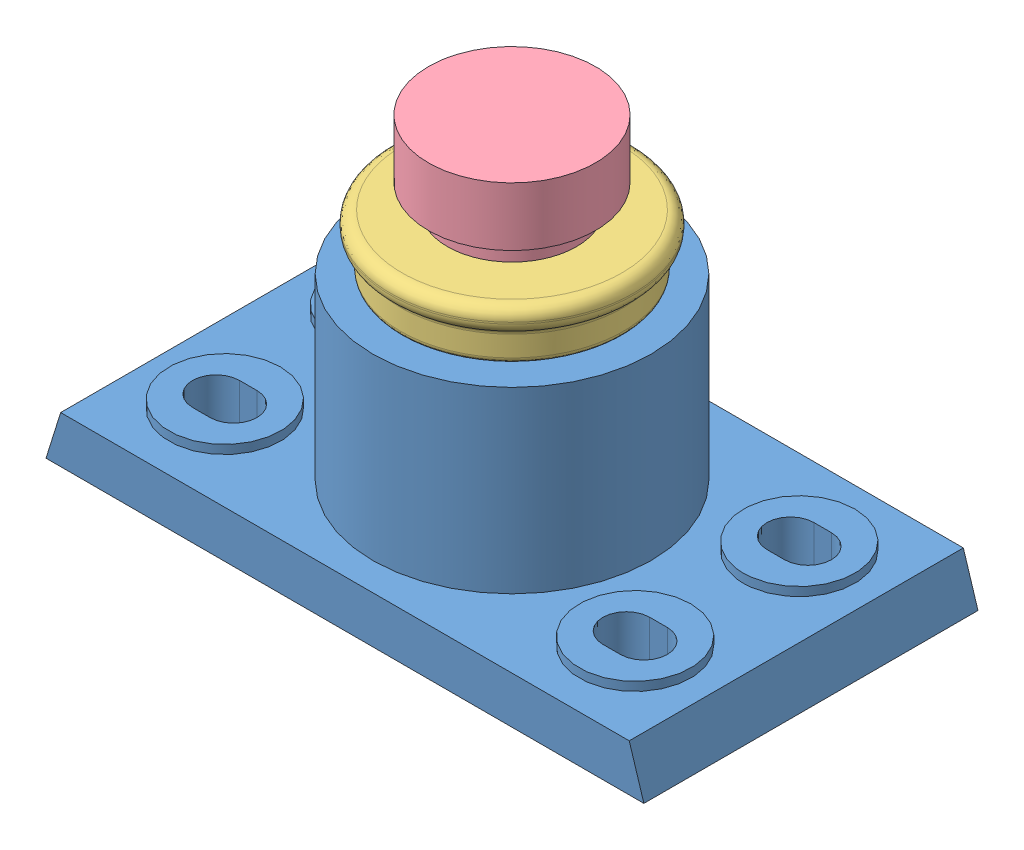
SolidWorks assembly Assembly, configuration Default. Lengths in mm.
Overall size (204 124 114).
4 component instances, 4 part files, 9 mates.
Components (placement in the parent):
- Body And Cavity 1-1: Body And Cavity 1 [Default] at (88.9394 52.143 160.5822) size (204 77 114)
- Pad and Pin Cavity-1: Pad and Pin Cavity [Default] at (88.9394 68.143 160.5822) size (44 13 44)
- Bush-2: Bush [Default] at (88.9394 148.143 160.5822) size (83 77 83)
- Shaft-1: Shaft [Default] at (88.9394 156.143 160.5822) x (-0.973997 0 -0.226562) z (0 1 0) size (57 57 95)
Mates (geometry in assembly coordinates):
- Concentric7: concentric anti-aligned: cylinder of Body And Cavity 1-1 through (88.9394 52.143 160.5822) axis (0 -1 0) radius 31; cylinder of Bush-2 through (88.9394 148.143 160.5822) axis (0 1 0) radius 31
- Concentric8: concentric anti-aligned: cylinder of Body And Cavity 1-1 through (88.9394 52.143 160.5822) axis (0 -1 0) radius 31; cylinder of Bush-2 through (88.9394 148.143 160.5822) axis (0 1 0) radius 31
- Concentric9: concentric anti-aligned: cylinder of Body And Cavity 1-1 through (110.9394 63.143 160.5822) axis (0 1 0) radius 1.5; cylinder of Bush-2 through (110.9394 76.143 160.5822) axis (0 -1 0) radius 1.5
- Coincident3: coincident anti-aligned: plane of Body And Cavity 1-1 through (119.9394 129.143 160.5822) normal (0 1 0); plane of Bush-2 through (126.9394 129.143 160.5822) normal (0 -1 0)
- Concentric18: concentric aligned: cylinder of Bush-2 through (88.9394 71.143 160.5822) axis (0 1 0) radius 22; cylinder of Shaft-1 through (88.9394 81.143 160.5822) axis (0 1 0) radius 22
- Tangent3: tangent anti-aligned: sphere of Pad and Pin Cavity-1; plane of Shaft-1 through (88.9394 81.143 160.5822) normal (0 -1 0)
- Coincident6: coincident anti-aligned: plane of Body And Cavity 1-1 through (185.9394 68.143 217.5822) normal (0 1 0); plane of Pad and Pin Cavity-1
- Concentric19: concentric aligned: cylinder of Pad and Pin Cavity-1 through (88.9394 95.1347 160.5822) axis (0 1 0) radius 22; cylinder of Bush-2 through (88.9394 71.143 160.5822) axis (0 1 0) radius 22
- Concentric20: concentric anti-aligned: cylinder of Body And Cavity 1-1 through (110.9394 63.143 160.5822) axis (0 1 0) radius 1.5; cylinder of Pad and Pin Cavity-1 through (110.9394 73.143 160.5822) axis (0 -1 0) radius 1.5
